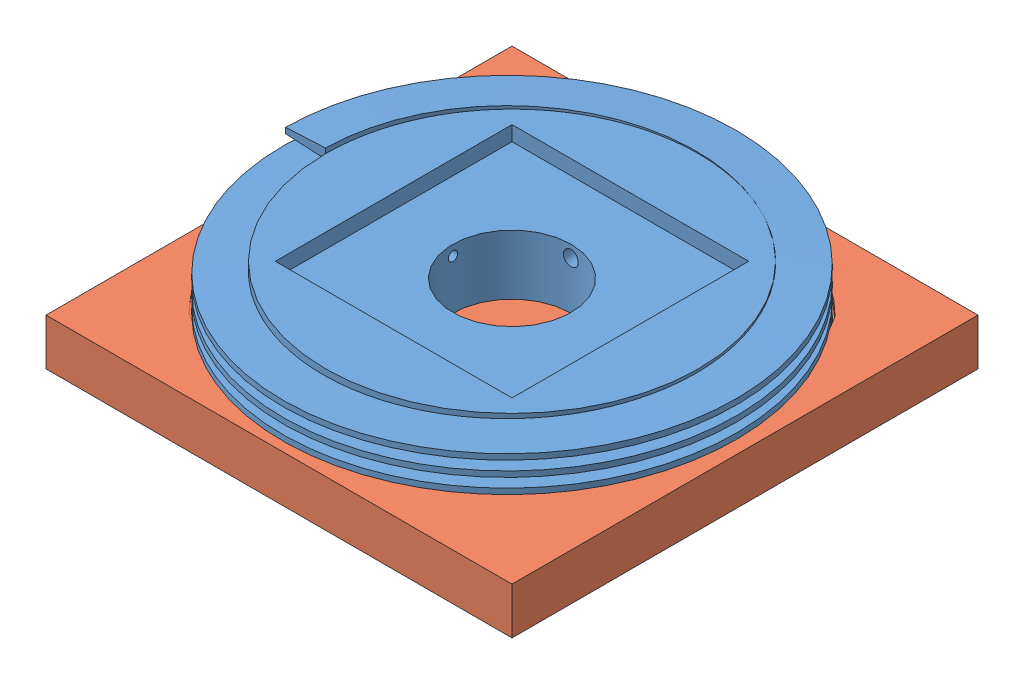
SolidWorks assembly ASI7, configuration Default. Lengths in mm.
Overall size (50.67 10.64 50).
2 component instances, 2 part files, 2 mates.
Components (placement in the parent):
- ASI7-1: ASI7 [Default] at (0 2.7806 0) x (1 0 0.000011) z (-0.000011 0 1) size (49.97 8.79 48.66)
- Bottom-1: Bottom [Default] at (0 2.7806 0) x (0.000011 0 -1) z (0 1 0) size (50 50 10.64)
Mates (geometry in assembly coordinates):
- Coincident2: coincident anti-aligned: line of ASI7-1 through (8 0 10.7806) axis (0 0 -1); line of Bottom-1 through (10 0 0.7806) axis (0 0 1)
- Screw1: screw = 0.625 aligned: cylinder of ASI7-1 through (0 10.7806 0) axis (0 -1 0) radius 20; cylinder of Bottom-1 through (0 10.7806 0) axis (0 -1 0) radius 20
